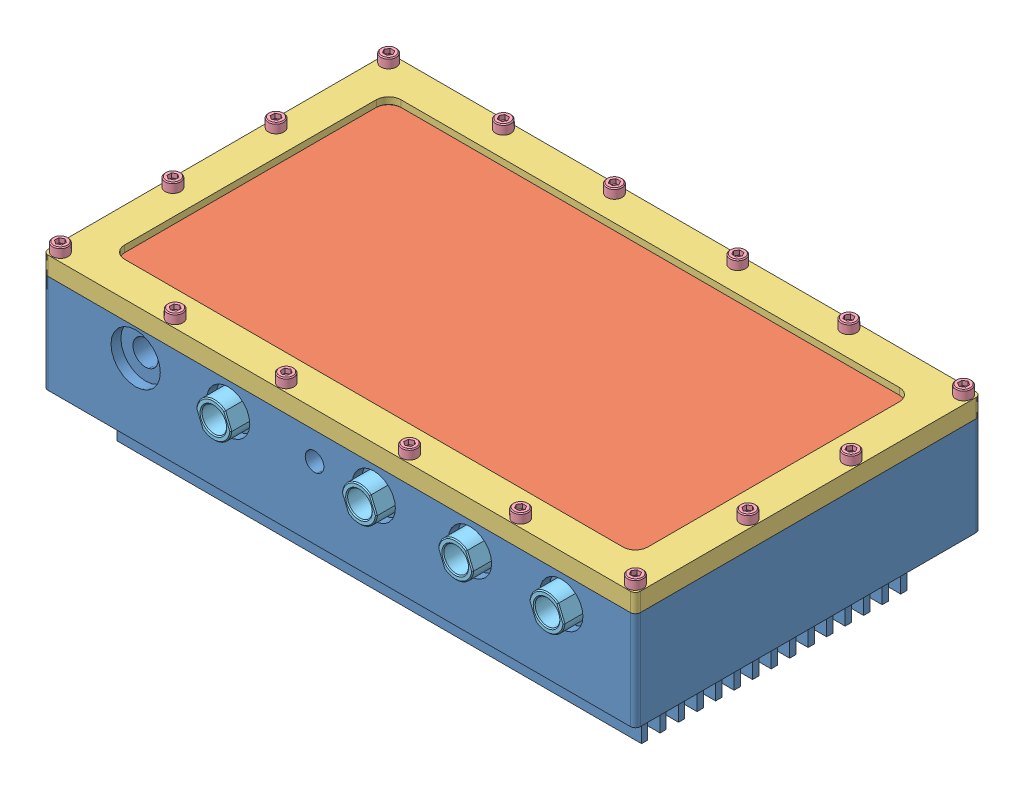
SolidWorks assembly 220300 - Motor Housing Final Assembly, configuration Default. Lengths in mm.
Overall size (306.9 90.55 193.04).
28 component instances, 6 part files, 56 mates.
Components (placement in the parent):
- PN220301 - Motor Housing main REV3-1: PN220301 - Motor Housing main REV3 [Default] at (-98.7437 133.6463 345.9652) size (304.8 76.2 177.8)
- 220303 - Motor Housing LID ACRYLIC REV2-1: 220303 - Motor Housing LID ACRYLIC REV2 [Default] at (-90.1077 215.6883 337.3292) x (0 0 -1) z (-1 0 0) size (160.53 5.97 287.53)
- 220302 - Motor Housing LID ALUMINUM REV2-1: 220302 - Motor Housing LID ALUMINUM REV2 [Default] at (-98.7437 219.3713 345.9652) x (0 0 -1) z (-1 0 0) size (177.8 9.53 304.8)
- socket head cap screw_ai-6: socket head cap screw_ai [HX-SHCS 0.19-24x0.75x0.75-N] at (85.4063 224.1973 341.5202) x (0 -1 0) z (-0.546944 0 0.837169) size (23.88 7.94 7.94)
- socket head cap screw_ai-7: socket head cap screw_ai [HX-SHCS 0.19-24x0.75x0.75-N] at (21.9063 224.1973 341.5202) x (0 -1 0) z (-0.546944 0 0.837169) size (23.88 7.94 7.94)
- socket head cap screw_ai-8: socket head cap screw_ai [HX-SHCS 0.19-24x0.75x0.75-N] at (-35.2437 224.1973 341.5202) x (0 -1 0) z (-0.546944 0 0.837169) size (23.88 7.94 7.94)
- socket head cap screw_ai-9: socket head cap screw_ai [HX-SHCS 0.19-24x0.75x0.75-N] at (-94.2987 224.1973 341.5202) x (0 -1 0) z (-0.546944 0 0.837169) size (23.88 7.94 7.94)
- socket head cap screw_ai-10: socket head cap screw_ai [HX-SHCS 0.19-24x0.75x0.75-N] at (-94.2987 224.1973 283.6082) x (0 -1 0) z (-0.546944 0 0.837169) size (23.88 7.94 7.94)
- socket head cap screw_ai-11: socket head cap screw_ai [HX-SHCS 0.19-24x0.75x0.75-N] at (-94.2987 224.1973 230.5222) x (0 -1 0) z (-0.546944 0 0.837169) size (23.88 7.94 7.94)
- socket head cap screw_ai-12: socket head cap screw_ai [HX-SHCS 0.19-24x0.75x0.75-N] at (-94.2987 224.1973 172.6102) x (0 -1 0) z (0 0 1) size (23.88 7.94 7.94)
- socket head cap screw_ai-13: socket head cap screw_ai [HX-SHCS 0.19-24x0.75x0.75-N] at (-35.2437 224.1973 172.6102) x (0 -1 0) z (0 0 1) size (23.88 7.94 7.94)
- socket head cap screw_ai-14: socket head cap screw_ai [HX-SHCS 0.19-24x0.75x0.75-N] at (21.9063 224.1973 172.6102) x (0 -1 0) z (0 0 1) size (23.88 7.94 7.94)
- socket head cap screw_ai-15: socket head cap screw_ai [HX-SHCS 0.19-24x0.75x0.75-N] at (85.4063 224.1973 172.6102) x (0 -1 0) z (0 0 1) size (23.88 7.94 7.94)
- socket head cap screw_ai-16: socket head cap screw_ai [HX-SHCS 0.19-24x0.75x0.75-N] at (142.5563 224.1973 172.6102) x (0 -1 0) z (0 0 1) size (23.88 7.94 7.94)
- socket head cap screw_ai-17: socket head cap screw_ai [HX-SHCS 0.19-24x0.75x0.75-N] at (201.6113 224.1973 172.6102) x (0 -1 0) z (1 0 0) size (23.88 7.94 7.94)
- socket head cap screw_ai-18: socket head cap screw_ai [HX-SHCS 0.19-24x0.75x0.75-N] at (201.6113 224.1973 230.5222) x (0 -1 0) z (0 0 1) size (23.88 7.94 7.94)
- socket head cap screw_ai-19: socket head cap screw_ai [HX-SHCS 0.19-24x0.75x0.75-N] at (201.6113 224.1973 283.6082) x (0 -1 0) z (-0.546944 0 0.837169) size (23.88 7.94 7.94)
- socket head cap screw_ai-20: socket head cap screw_ai [HX-SHCS 0.19-24x0.75x0.75-N] at (201.6113 224.1973 341.5202) x (0 -1 0) z (0 0 1) size (23.88 7.94 7.94)
- socket head cap screw_ai-21: socket head cap screw_ai [HX-SHCS 0.19-24x0.75x0.75-N] at (142.5563 224.1973 341.5202) x (0 -1 0) z (0 0 1) size (23.88 7.94 7.94)
- 6mm PEN-1: 6mm PEN [Default] at (167.9563 195.8763 160.5452) x (0 0 1) z (-0.923728 -0.383049 0) size (37.59 18.03 16)
- 6mm PEN-2: 6mm PEN [Default] at (120.9663 195.8763 160.5452) x (0 0 1) z (-0.923728 -0.383049 0) size (37.59 18.03 16)
- 6mm PEN-3: 6mm PEN [Default] at (71.4363 195.8763 160.5452) x (0 0 1) z (-0.923728 -0.383049 0) size (37.59 18.03 16)
- 6mm PEN-4: 6mm PEN [Default] at (-3.4937 195.8763 160.5452) x (0 0 1) z (-0.923728 -0.383049 0) size (37.59 18.03 16)
- 6mm PEN-5: 6mm PEN [Default] at (167.9563 195.8763 353.5852) x (0 0 -1) z (0.923728 0.383049 0) size (37.59 18.03 16)
- 6mm PEN-6: 6mm PEN [Default] at (120.9663 195.8763 353.5852) x (0 0 -1) z (0.923728 0.383049 0) size (37.59 18.03 16)
- 6mm PEN-7: 6mm PEN [Default] at (-3.4937 195.8763 353.5852) x (0 0 -1) z (0.923728 0.383049 0) size (37.59 18.03 16)
- 6mm PEN-8: 6mm PEN [Default] at (71.4363 195.8763 353.5852) x (0 0 -1) z (0.923728 0.383049 0) size (37.59 18.03 16)
- 8mm PEN-1: 8mm PEN [Default] at (-51.1187 195.8763 160.5452) x (0 0 1) z (-0.832194 -0.554484 0) size (37.59 18.03 16)
Mates (geometry in assembly coordinates):
- Coincident1: coincident anti-aligned: plane of 220303 - Motor Housing LID ACRYLIC REV2-1 through (-90.1077 215.6883 337.3292) normal (0 1 0); plane of 220302 - Motor Housing LID ALUMINUM REV2-1 through (181.9263 215.6883 321.8352) normal (0 -1 0)
- Coincident2: coincident anti-aligned: plane of 220303 - Motor Housing LID ACRYLIC REV2-1 through (197.4203 209.7193 337.3292) normal (1 0 0); plane of 220302 - Motor Housing LID ALUMINUM REV2-1 through (197.4203 215.6883 192.2952) normal (-1 0 0)
- Coincident3: coincident anti-aligned: plane of 220303 - Motor Housing LID ACRYLIC REV2-1 through (-90.1077 209.7193 337.3292) normal (0 0 1); plane of 220302 - Motor Housing LID ALUMINUM REV2-1 through (181.9263 215.6883 337.3292) normal (0 0 -1)
- Coincident4: coincident anti-aligned: plane of PN220301 - Motor Housing main REV3-1 through (-98.7437 209.8463 345.9652) normal (0 1 0); plane of 220302 - Motor Housing LID ALUMINUM REV2-1 through (-98.7437 209.8463 345.9652) normal (0 -1 0)
- Concentric1: concentric anti-aligned: cylinder of PN220301 - Motor Housing main REV3-1 through (201.6113 209.8463 172.6102) axis (0 1 0) radius 1.8986; cylinder of 220302 - Motor Housing LID ALUMINUM REV2-1 through (201.6113 219.3713 172.6102) axis (0 -1 0) radius 2.5527
- Concentric2: concentric anti-aligned: cylinder of 220302 - Motor Housing LID ALUMINUM REV2-1 through (-94.2987 219.3713 341.5202) axis (0 -1 0) radius 2.5527; cylinder of PN220301 - Motor Housing main REV3-1 through (-94.2987 209.8463 341.5202) axis (0 1 0) radius 1.8986
- Concentric3: concentric anti-aligned: cylinder of 220302 - Motor Housing LID ALUMINUM REV2-1 through (85.4063 219.3713 341.5202) axis (0 -1 0) radius 2.5527; cylinder of socket head cap screw_ai-6 through (85.4063 255.9473 341.5202) axis (0 1 0) radius 3.9688
- Coincident6: coincident anti-aligned: plane of 220302 - Motor Housing LID ALUMINUM REV2-1 through (-98.7437 219.3713 345.9652) normal (0 1 0); plane of socket head cap screw_ai-6 through (88.7288 219.3713 343.6909) normal (0 -1 0)
- Concentric4: concentric anti-aligned: cylinder of 220302 - Motor Housing LID ALUMINUM REV2-1 through (21.9063 219.3713 341.5202) axis (0 -1 0) radius 2.5527; cylinder of socket head cap screw_ai-7 through (21.9063 255.9473 341.5202) axis (0 1 0) radius 3.9688
- Coincident7: coincident anti-aligned: plane of 220302 - Motor Housing LID ALUMINUM REV2-1 through (-98.7437 219.3713 345.9652) normal (0 1 0); plane of socket head cap screw_ai-7 through (25.2288 219.3713 343.6909) normal (0 -1 0)
- Concentric5: concentric anti-aligned: cylinder of 220302 - Motor Housing LID ALUMINUM REV2-1 through (-35.2437 219.3713 341.5202) axis (0 -1 0) radius 2.5527; cylinder of socket head cap screw_ai-8 through (-35.2437 255.9473 341.5202) axis (0 1 0) radius 3.9688
- Coincident8: coincident anti-aligned: plane of 220302 - Motor Housing LID ALUMINUM REV2-1 through (-98.7437 219.3713 345.9652) normal (0 1 0); plane of socket head cap screw_ai-8 through (-31.9212 219.3713 343.6909) normal (0 -1 0)
- Concentric6: concentric anti-aligned: cylinder of 220302 - Motor Housing LID ALUMINUM REV2-1 through (-94.2987 219.3713 341.5202) axis (0 -1 0) radius 2.5527; cylinder of socket head cap screw_ai-9 through (-94.2987 255.9473 341.5202) axis (0 1 0) radius 3.9688
- Coincident9: coincident anti-aligned: plane of 220302 - Motor Housing LID ALUMINUM REV2-1 through (-98.7437 219.3713 345.9652) normal (0 1 0); plane of socket head cap screw_ai-9 through (-90.9762 219.3713 343.6909) normal (0 -1 0)
- Concentric7: concentric anti-aligned: cylinder of 220302 - Motor Housing LID ALUMINUM REV2-1 through (-94.2987 219.3713 283.6082) axis (0 -1 0) radius 2.5527; cylinder of socket head cap screw_ai-10 through (-94.2987 255.9473 283.6082) axis (0 1 0) radius 3.9688
- Coincident10: coincident anti-aligned: plane of 220302 - Motor Housing LID ALUMINUM REV2-1 through (-98.7437 219.3713 345.9652) normal (0 1 0); plane of socket head cap screw_ai-10 through (-90.9762 219.3713 285.7789) normal (0 -1 0)
- Concentric8: concentric anti-aligned: cylinder of 220302 - Motor Housing LID ALUMINUM REV2-1 through (-94.2987 219.3713 230.5222) axis (0 -1 0) radius 2.5527; cylinder of socket head cap screw_ai-11 through (-94.2987 255.9473 230.5222) axis (0 1 0) radius 3.9688
- Coincident11: coincident anti-aligned: plane of 220302 - Motor Housing LID ALUMINUM REV2-1 through (-98.7437 219.3713 345.9652) normal (0 1 0); plane of socket head cap screw_ai-11 through (-90.9762 219.3713 232.6929) normal (0 -1 0)
- Concentric9: concentric anti-aligned: cylinder of 220302 - Motor Housing LID ALUMINUM REV2-1 through (-94.2987 219.3713 172.6102) axis (0 -1 0) radius 2.5527; cylinder of socket head cap screw_ai-12 through (-94.2987 255.9473 172.6102) axis (0 1 0) radius 3.9688
- Coincident12: coincident anti-aligned: plane of 220302 - Motor Housing LID ALUMINUM REV2-1 through (-98.7437 219.3713 345.9652) normal (0 1 0); plane of socket head cap screw_ai-12 through (-90.33 219.3713 172.6102) normal (0 -1 0)
- Concentric10: concentric anti-aligned: cylinder of 220302 - Motor Housing LID ALUMINUM REV2-1 through (-35.2437 219.3713 172.6102) axis (0 -1 0) radius 2.5527; cylinder of socket head cap screw_ai-13 through (-35.2437 255.9473 172.6102) axis (0 1 0) radius 3.9688
- Coincident13: coincident anti-aligned: plane of 220302 - Motor Housing LID ALUMINUM REV2-1 through (-98.7437 219.3713 345.9652) normal (0 1 0); plane of socket head cap screw_ai-13 through (-31.275 219.3713 172.6102) normal (0 -1 0)
- Concentric11: concentric anti-aligned: cylinder of 220302 - Motor Housing LID ALUMINUM REV2-1 through (21.9063 219.3713 172.6102) axis (0 -1 0) radius 2.5527; cylinder of socket head cap screw_ai-14 through (21.9063 255.9473 172.6102) axis (0 1 0) radius 3.9688
- Coincident14: coincident anti-aligned: plane of 220302 - Motor Housing LID ALUMINUM REV2-1 through (-98.7437 219.3713 345.9652) normal (0 1 0); plane of socket head cap screw_ai-14 through (25.875 219.3713 172.6102) normal (0 -1 0)
- Concentric12: concentric anti-aligned: cylinder of 220302 - Motor Housing LID ALUMINUM REV2-1 through (85.4063 219.3713 172.6102) axis (0 -1 0) radius 2.5527; cylinder of socket head cap screw_ai-15 through (85.4063 255.9473 172.6102) axis (0 1 0) radius 3.9688
- Coincident15: coincident anti-aligned: plane of 220302 - Motor Housing LID ALUMINUM REV2-1 through (-98.7437 219.3713 345.9652) normal (0 1 0); plane of socket head cap screw_ai-15 through (89.375 219.3713 172.6102) normal (0 -1 0)
- Concentric13: concentric anti-aligned: cylinder of 220302 - Motor Housing LID ALUMINUM REV2-1 through (142.5563 219.3713 172.6102) axis (0 -1 0) radius 2.5527; cylinder of socket head cap screw_ai-16 through (142.5563 255.9473 172.6102) axis (0 1 0) radius 3.9688
- Coincident16: coincident anti-aligned: plane of 220302 - Motor Housing LID ALUMINUM REV2-1 through (-98.7437 219.3713 345.9652) normal (0 1 0); plane of socket head cap screw_ai-16 through (146.525 219.3713 172.6102) normal (0 -1 0)
- Concentric14: concentric anti-aligned: cylinder of 220302 - Motor Housing LID ALUMINUM REV2-1 through (201.6113 219.3713 172.6102) axis (0 -1 0) radius 2.5527; cylinder of socket head cap screw_ai-17 through (201.6113 255.9473 172.6102) axis (0 1 0) radius 3.9688
- Coincident17: coincident anti-aligned: plane of 220302 - Motor Housing LID ALUMINUM REV2-1 through (-98.7437 219.3713 345.9652) normal (0 1 0); plane of socket head cap screw_ai-17 through (201.6113 219.3713 168.6414) normal (0 -1 0)
- Concentric15: concentric anti-aligned: cylinder of 220302 - Motor Housing LID ALUMINUM REV2-1 through (201.6113 219.3713 230.5222) axis (0 -1 0) radius 2.5527; cylinder of socket head cap screw_ai-18 through (201.6113 255.9473 230.5222) axis (0 1 0) radius 3.9688
- Coincident18: coincident anti-aligned: plane of 220302 - Motor Housing LID ALUMINUM REV2-1 through (-98.7437 219.3713 345.9652) normal (0 1 0); plane of socket head cap screw_ai-18 through (205.58 219.3713 230.5222) normal (0 -1 0)
- Concentric16: concentric anti-aligned: cylinder of 220302 - Motor Housing LID ALUMINUM REV2-1 through (201.6113 219.3713 283.6082) axis (0 -1 0) radius 2.5527; cylinder of socket head cap screw_ai-19 through (201.6113 255.9473 283.6082) axis (0 1 0) radius 3.9688
- Coincident19: coincident anti-aligned: plane of 220302 - Motor Housing LID ALUMINUM REV2-1 through (-98.7437 219.3713 345.9652) normal (0 1 0); plane of socket head cap screw_ai-19 through (204.9338 219.3713 285.7789) normal (0 -1 0)
- Concentric17: concentric anti-aligned: cylinder of 220302 - Motor Housing LID ALUMINUM REV2-1 through (201.6113 219.3713 341.5202) axis (0 -1 0) radius 2.5527; cylinder of socket head cap screw_ai-20 through (201.6113 255.9473 341.5202) axis (0 1 0) radius 3.9688
- Coincident20: coincident anti-aligned: plane of 220302 - Motor Housing LID ALUMINUM REV2-1 through (-98.7437 219.3713 345.9652) normal (0 1 0); plane of socket head cap screw_ai-20 through (205.58 219.3713 341.5202) normal (0 -1 0)
- Concentric18: concentric anti-aligned: cylinder of 220302 - Motor Housing LID ALUMINUM REV2-1 through (142.5563 219.3713 341.5202) axis (0 -1 0) radius 2.5527; cylinder of socket head cap screw_ai-21 through (142.5563 255.9473 341.5202) axis (0 1 0) radius 3.9688
- Coincident21: coincident anti-aligned: plane of 220302 - Motor Housing LID ALUMINUM REV2-1 through (-98.7437 219.3713 345.9652) normal (0 1 0); plane of socket head cap screw_ai-21 through (146.525 219.3713 341.5202) normal (0 -1 0)
- Concentric19: concentric aligned: cylinder of PN220301 - Motor Housing main REV3-1 through (167.9563 195.8763 168.1652) axis (0 0 -1) radius 5.0419; cylinder of 6mm PEN-1 through (167.9563 195.8763 198.1372) axis (0 0 -1) radius 5
- Concentric20: concentric aligned: cylinder of PN220301 - Motor Housing main REV3-1 through (120.9663 195.8763 168.1652) axis (0 0 -1) radius 5.0419; cylinder of 6mm PEN-2 through (120.9663 195.8763 198.1372) axis (0 0 -1) radius 5
- Concentric21: concentric aligned: cylinder of PN220301 - Motor Housing main REV3-1 through (71.4363 195.8763 168.1652) axis (0 0 -1) radius 5.0419; cylinder of 6mm PEN-3 through (71.4363 195.8763 198.1372) axis (0 0 -1) radius 5
- Concentric22: concentric aligned: cylinder of PN220301 - Motor Housing main REV3-1 through (-3.4937 195.8763 168.1652) axis (0 0 -1) radius 5.0419; cylinder of 6mm PEN-4 through (-3.4937 195.8763 198.1372) axis (0 0 -1) radius 5
- Concentric23: concentric aligned: cylinder of PN220301 - Motor Housing main REV3-1 through (-3.4937 195.8763 345.9652) axis (0 0 1) radius 5.0419; cylinder of 6mm PEN-7 through (-3.4937 195.8763 315.9932) axis (0 0 1) radius 5
- Concentric24: concentric aligned: cylinder of PN220301 - Motor Housing main REV3-1 through (71.4363 195.8763 345.9652) axis (0 0 1) radius 5.0419; cylinder of 6mm PEN-8 through (71.4363 195.8763 315.9932) axis (0 0 1) radius 5
- Concentric25: concentric aligned: cylinder of PN220301 - Motor Housing main REV3-1 through (120.9663 195.8763 345.9652) axis (0 0 1) radius 5.0419; cylinder of 6mm PEN-6 through (120.9663 195.8763 315.9932) axis (0 0 1) radius 5
- Concentric26: concentric aligned: cylinder of PN220301 - Motor Housing main REV3-1 through (167.9563 195.8763 345.9652) axis (0 0 1) radius 5.0419; cylinder of 6mm PEN-5 through (167.9563 195.8763 315.9932) axis (0 0 1) radius 5
- Coincident22: coincident anti-aligned: plane of PN220301 - Motor Housing main REV3-1 through (1.5482 195.8763 340.8852) normal (0 0 1); plane of 6mm PEN-7 through (-3.4937 195.8763 340.8852) normal (0 0 -1)
- Coincident23: coincident anti-aligned: plane of PN220301 - Motor Housing main REV3-1 through (76.4782 195.8763 340.8852) normal (0 0 1); plane of 6mm PEN-8 through (71.4363 195.8763 340.8852) normal (0 0 -1)
- Coincident24: coincident anti-aligned: plane of PN220301 - Motor Housing main REV3-1 through (126.0082 195.8763 340.8852) normal (0 0 1); plane of 6mm PEN-6 through (120.9663 195.8763 340.8852) normal (0 0 -1)
- Coincident25: coincident anti-aligned: plane of PN220301 - Motor Housing main REV3-1 through (172.9982 195.8763 340.8852) normal (0 0 1); plane of 6mm PEN-5 through (167.9563 195.8763 340.8852) normal (0 0 -1)
- Coincident26: coincident anti-aligned: plane of PN220301 - Motor Housing main REV3-1 through (172.9982 195.8763 173.2452) normal (0 0 -1); plane of 6mm PEN-1 through (167.9563 195.8763 173.2452) normal (0 0 1)
- Coincident27: coincident anti-aligned: plane of PN220301 - Motor Housing main REV3-1 through (126.0082 195.8763 173.2452) normal (0 0 -1); plane of 6mm PEN-2 through (120.9663 195.8763 173.2452) normal (0 0 1)
- Coincident28: coincident anti-aligned: plane of PN220301 - Motor Housing main REV3-1 through (76.4782 195.8763 173.2452) normal (0 0 -1); plane of 6mm PEN-3 through (71.4363 195.8763 173.2452) normal (0 0 1)
- Coincident29: coincident anti-aligned: plane of PN220301 - Motor Housing main REV3-1 through (1.5482 195.8763 173.2452) normal (0 0 -1); plane of 6mm PEN-4 through (-3.4937 195.8763 173.2452) normal (0 0 1)
- Concentric27: concentric aligned: cylinder of PN220301 - Motor Housing main REV3-1 through (-51.1187 195.8763 168.1652) axis (0 0 -1) radius 6.5024; cylinder of 8mm PEN-1 through (-51.1187 195.8763 198.1372) axis (0 0 -1) radius 5
- Coincident30: coincident anti-aligned: plane of PN220301 - Motor Housing main REV3-1 through (-44.6163 195.8763 173.2452) normal (0 0 -1); plane of 8mm PEN-1 through (-51.1187 195.8763 173.2452) normal (0 0 1)
